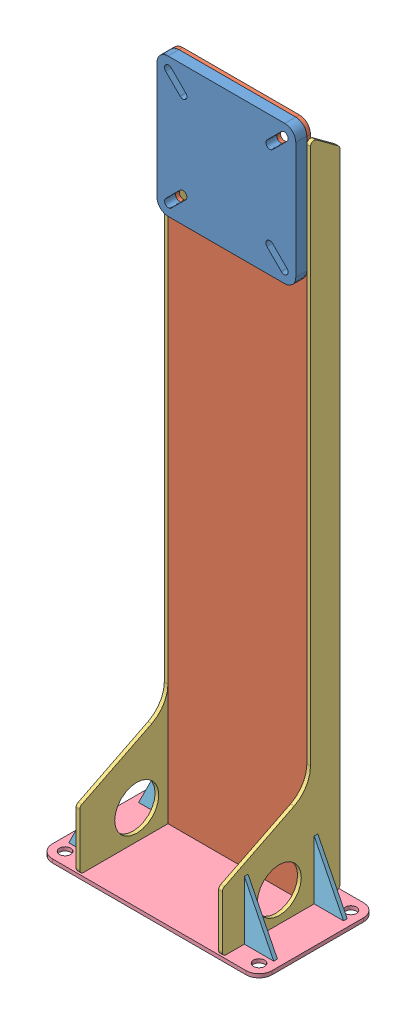
SolidWorks assembly 32 inch mount, configuration Default. Lengths in mm.
Overall size (189.85 587.38 101.6).
9 component instances, 5 part files, 8 mates.
Components (placement in the parent):
- FacePlate-1: FacePlate [Default] at origin size (120 120 9.53)
- Part2^32 inch mount-1: Part2^32 inch mount [Default] x (-1 0 0) z (0 0 -1) size (120 584.2 3.17) (virtual)
- Part3^32 inch mount-1: Part3^32 inch mount [Default] at origin size (3.17 571.56 101.6) (virtual)
- Part3^32 inch mount-2: Part3^32 inch mount [Default] at (-123.175 0 0) size (3.17 571.56 101.6) (virtual)
- Part4^32 inch mount-1: Part4^32 inch mount [Default] at (0 -524.2 0) x (1 0 0) z (0 -1 0) size (189.85 101.6 3.17) (virtual)
- Part5^32 inch mount-1: Part5^32 inch mount [Default] at origin size (25.4 50.8 3.17) (virtual)
- Part5^32 inch mount-2: Part5^32 inch mount [Default] at (0 0 60.325) size (25.4 50.8 3.17) (virtual)
- Part5^32 inch mount-3: Part5^32 inch mount [Default] at (0 0 -9.525) x (-1 0 0) z (0 0 -1) size (25.4 50.8 3.17) (virtual)
- Part5^32 inch mount-4: Part5^32 inch mount [Default] at (0 0 50.8) x (-1 0 0) z (0 0 -1) size (25.4 50.8 3.17) (virtual)
Mates (geometry in assembly coordinates):
- InPlace1: in place: plane of ? through (0 0 -3.175) normal (0 0 -1); plane of ? through (0 0 -3.175) normal (0 0 -1); moOrthogonalPlaneRef_w of ? through (0 0 -3.175) normal (0 0 -1); plane of ? through (0 0 -3.175) normal (0 1 0); plane of ? through (0 0 -3.175) normal (0 0 -1); plane of ? through (0 0 -3.175) normal (-1 0 0); plane of ? through (0 0 0) normal (0 0 -1); unknown of Part2^32 inch mount-1
- Coincident1: coincident aligned: plane of FacePlate-1; plane of Part2^32 inch mount-1
- Coincident2: coincident aligned: moOrthogonalPlaneRef_w of FacePlate-1 through (0 0 0) normal (0 1 0); plane of Part2^32 inch mount-1 through (0 0 0) normal (0 1 0)
- Coincident3: coincident anti-aligned: moOrthogonalPlaneRef_w of FacePlate-1 through (0 0 0) normal (1 0 0); plane of Part2^32 inch mount-1 through (0 0 0) normal (-1 0 0)
- InPlace2: in place: plane of Part2^32 inch mount-1 through (60 -524.2 -3.175) normal (0 -1 0); plane of ? through (0 -524.2 0) normal (0 -1 0); plane of Part2^32 inch mount-1 through (60 -524.2 -3.175) normal (0 -1 0); plane of ? through (0 -524.2 0) normal (0 0 -1); plane of Part2^32 inch mount-1 through (60 -524.2 -3.175) normal (0 -1 0); plane of ? through (0 -524.2 0) normal (-1 0 0); plane of Part2^32 inch mount-1 through (60 -524.2 -3.175) normal (0 -1 0); unknown of Part4^32 inch mount-1
- Coincident4: coincident aligned: plane of Part2^32 inch mount-1; plane of Part4^32 inch mount-1
- Coincident5: coincident aligned: moOrthogonalPlaneRef_w of Part2^32 inch mount-1 through (0 -524.2 0) normal (0 0 1); plane of Part4^32 inch mount-1 through (0 -524.2 0) normal (0 0 1)
- Coincident6: coincident anti-aligned: moOrthogonalPlaneRef_w of Part2^32 inch mount-1 through (0 -524.2 0) normal (-1 0 0); plane of Part4^32 inch mount-1 through (0 -524.2 0) normal (1 0 0)
